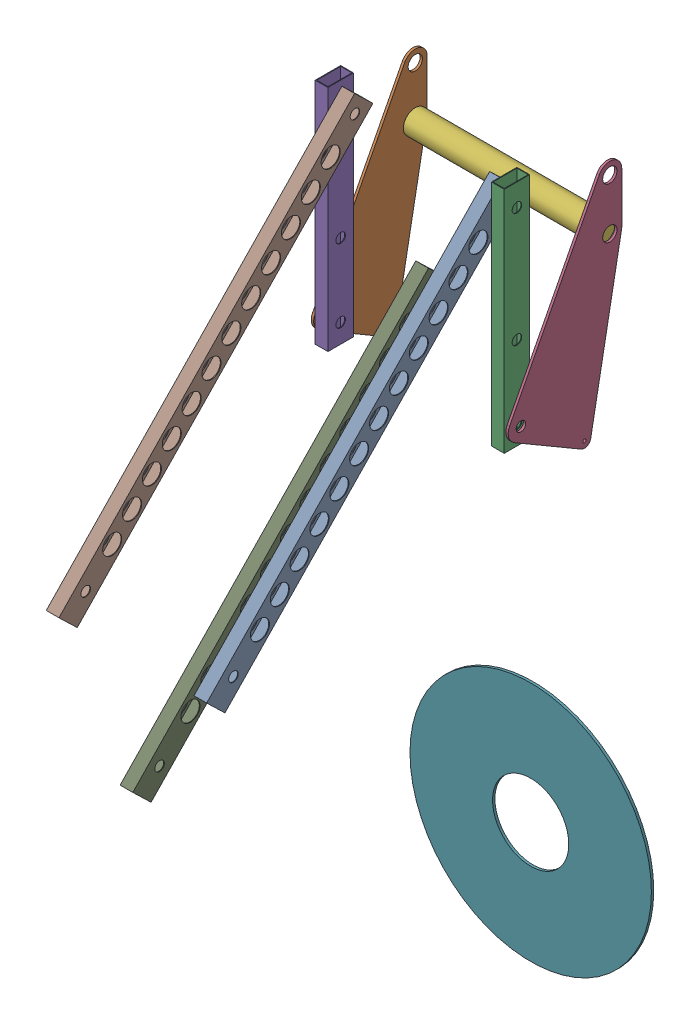
SolidWorks assembly AM14U4_Square_2019_custom, configuration Default. Lengths in mm.
Overall size (482.6 1537.66 803.01).
10 component instances, 6 part files, 0 mates.
Components (placement in the parent):
- lift_arm_Default_As Machined_-1: lift_arm_Default_As Machined_ [Default] at (59.2314 1055.4176 330.4872) x (0 0.719327 -0.694672) z (-1 0 0) size (850.9 50.8 25.4)
- intake_3-1: intake_3 [Default] at (8.5469 1127.7585 -504.7249) size (393.82 520.7 236.69)
  - intake_side_rev3SLDPRT-1: intake_side_rev3SLDPRT [Default] at (-293.803 45.2132 287.1603) size (4.76 471.49 227.01)
  - end_link_Default_As Machined_-1: end_link_Default_As Machined_ [Default] at (79.2595 108.7132 261.7603) size (25.4 457.2 50.8)
  - intake_side_rev3SLDPRT-2: intake_side_rev3SLDPRT [Default] at (95.1345 45.2132 287.1603) size (4.76 471.49 227.01)
  - end_link_Default_As Machined_-2: end_link_Default_As Machined_ [Default] at (-273.1655 108.7132 261.7603) size (25.4 457.2 50.8)
  - intake_roller-1: intake_roller [Default] at (-293.9207 391.2882 83.9603) x (1 0 0) z (0 0.77759 0.628772) size (381 47.62 47.62)
- HATCH_PANEL-1: HATCH_PANEL [Default] at (-73.656 397.3156 -449.3397) size (482.6 482.6 4.76)
- lift_arm_Default_As Machined_-2: lift_arm_Default_As Machined_ [Default] at (-236.0436 1055.4176 330.4872) x (0 0.719327 -0.694672) z (-1 0 0) size (850.9 50.8 25.4)
- lower_lift_arm_Default_As Machined_-1: lower_lift_arm_Default_As Machined_ [Default] at (-88.4061 826.8176 330.4872) x (0 0.719327 -0.694672) z (1 0 0) size (850.9 50.8 25.4)
